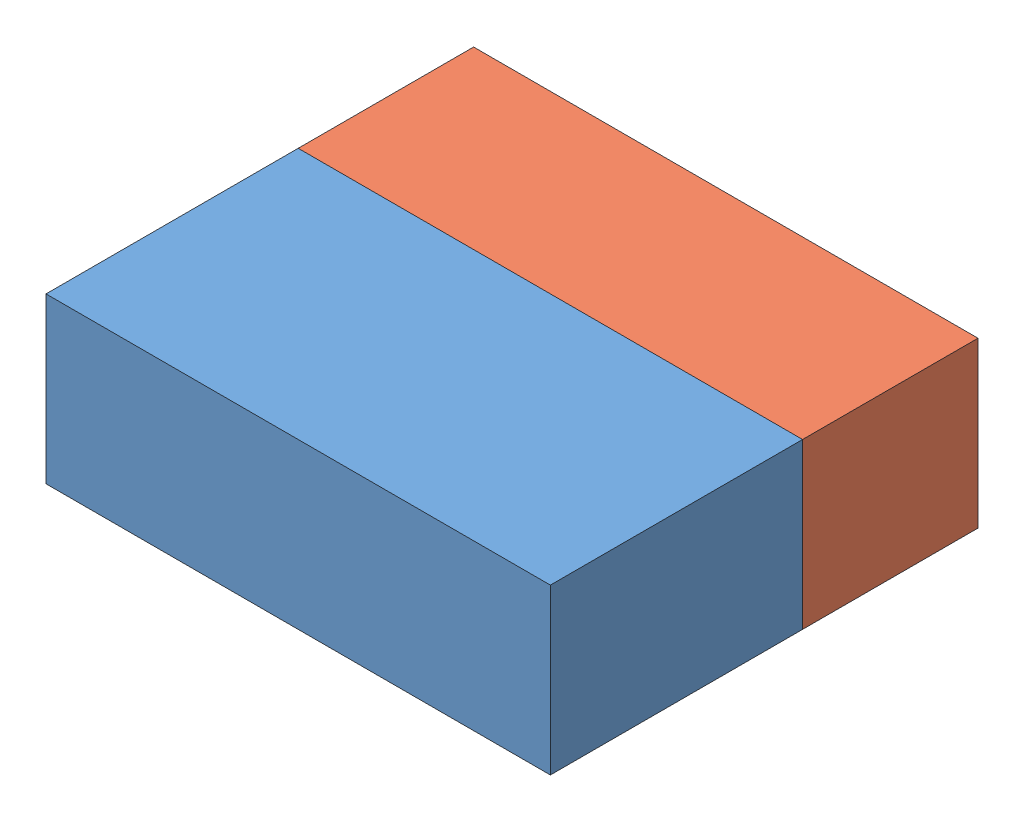
SolidWorks assembly Assem4, configuration Default. Lengths in mm.
Overall size (230 75 195).
2 component instances, 2 part files, 2 mates.
Components (placement in the parent):
- Brick-Sharp-1: Brick-Sharp [Default] at (80.1081 128.5759 173.7678) size (230 75 115)
- Brick-Sharp-Trimmed-1: Brick-Sharp-Trimmed [Default] at (80.1081 128.5759 58.7678) size (230 75 80)
Mates (geometry in assembly coordinates):
- Coincident1: coincident: plane of Brick-Sharp-1 through (-34.8919 166.0759 116.2678) normal (0 0 -1); plane of Brick-Sharp-Trimmed-1 through (-34.8919 166.0759 116.2678) normal (0 0 1)
- Coincident3: coincident aligned: line of Brick-Sharp-1 through (195.1081 91.0759 231.2678) axis (0 0 -1); line of Brick-Sharp-Trimmed-1 through (195.1081 91.0759 116.2678) axis (0 0 -1)
